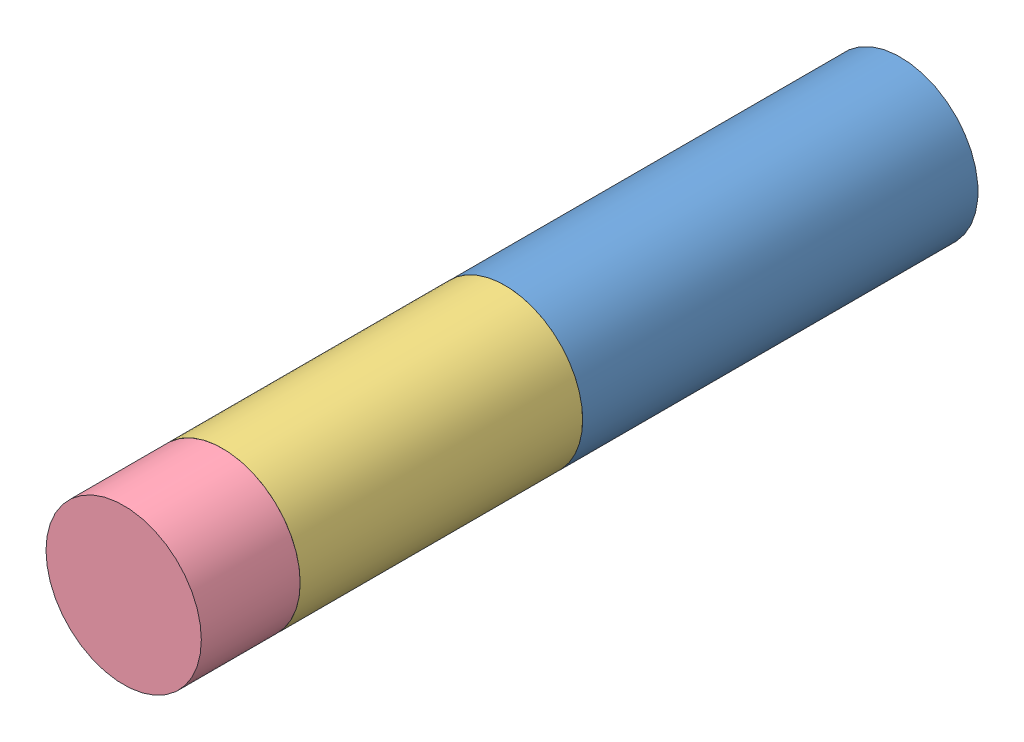
SolidWorks assembly Ensamblaje1, configuration Predeterminado. Lengths in mm.
Overall size (22 22 112).
5 component instances, 5 part files, 7 mates.
Components (placement in the parent):
- Base motor y resorte-1: Base motor y resorte [Predeterminado] at (-0.2893 -0.5465 56) size (22 22 56)
- dc_motor-2: dc_motor [Default] at (-0.2893 -0.5465 63.6) x (0 0 -1) z (-1 0 0) size (62.2 10 12)
- enclaje-5: enclaje [Predeterminado] at (-0.2893 -0.5465 147) x (1 0 0) z (0 0 -1) size (22 22 40)
- Perno de anclaje y explusion-3: Perno de anclaje y explusion [Predeterminado] at (-0.2893 -0.5465 137) x (1 0 0) z (0 0 -1) size (22 22 54)
- resorte - comprimido-3: resorte - comprimido [Predeterminado] at (-0.2994 -0.5491 82.6751) x (1 0 0) z (0 -1 0) size (9.46 30.05 9)
Mates (geometry in assembly coordinates):
- Coincidente2: coincident anti-aligned: plane of Base motor y resorte-1 through (-6.2893 4.4535 82) normal (0 -1 0); plane of dc_motor-2 through (-6.2893 4.4535 71.2) normal (0 1 0)
- Coincidente3: coincident: line of Base motor y resorte-1 through (-6.2893 4.4535 56) axis (0 -1 0); plane of dc_motor-2 through (-6.2893 4.4535 56) normal (0 0 -1)
- Coincidente4: coincident aligned: line of Base motor y resorte-1 through (-6.2893 4.4535 56) axis (0 -1 0); line of dc_motor-2 through (-6.2893 1.9535 56) axis (0 -1 0)
- Coincidente7: coincident anti-aligned: plane of Base motor y resorte-1 through (-0.2893 -0.5465 112) normal (0 0 1); plane of enclaje-5 through (-0.2893 -0.5465 112) normal (0 0 -1)
- Coincidente8: coincident anti-aligned: circle of Base motor y resorte-1; circle of enclaje-5
- Coincidente12: coincident anti-aligned: plane of enclaje-5 through (-0.2893 -0.5465 152) normal (0 0 1); plane of Perno de anclaje y explusion-3 through (-0.2893 -0.5465 152) normal (0 0 -1)
- Coincidente13: coincident aligned: circle of enclaje-5; circle of Perno de anclaje y explusion-3
